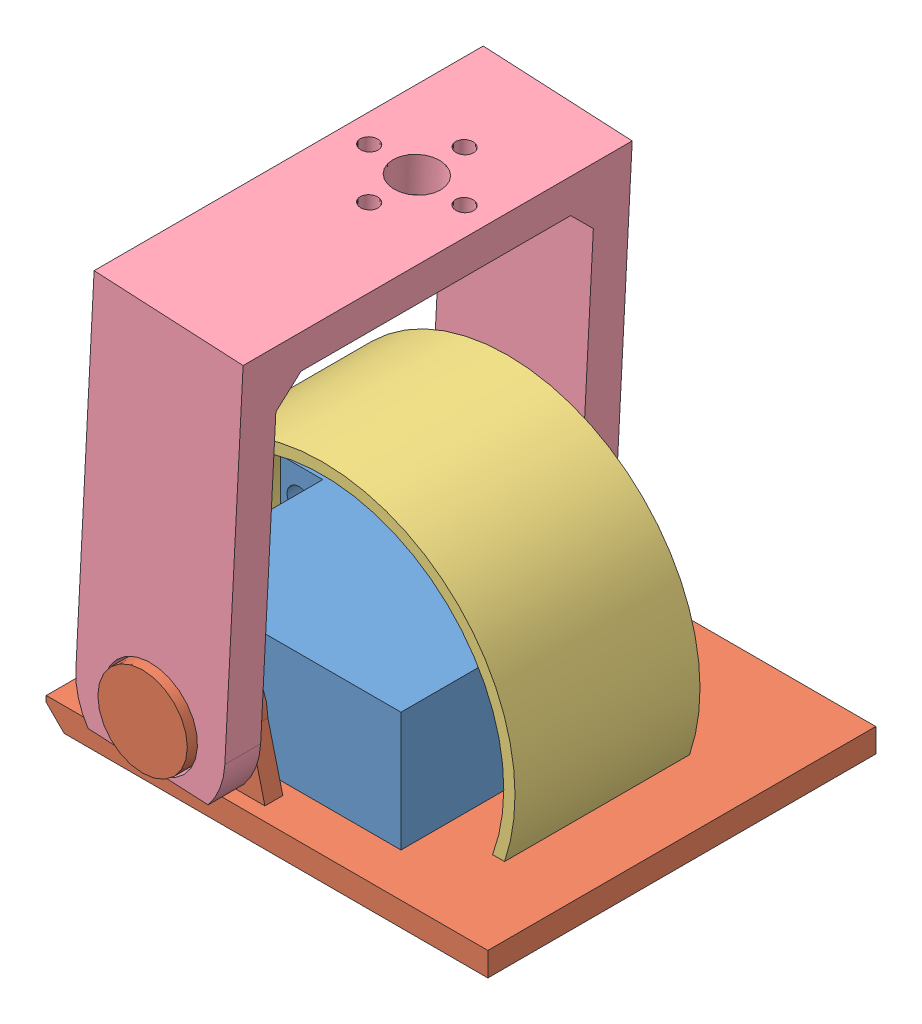
SolidWorks assembly Montaje, configuration Predeterminado. Lengths in mm.
Overall size (74.26 74.06 70.7).
4 component instances, 4 part files, 10 mates.
Components (placement in the parent):
- motor 996R-1: motor 996R [Predeterminado] at (-11.5098 -10.0295 59.1) size (54.5 21 47.5)
- Pie_DER-1: Pie_DER [Predeterminado] at (-9.5891 -14.0295 56.1) x (-1 0 0) z (0 0 -1) size (74 27.39 70.7)
- Zapato_DER-1: Zapato_DER [Predeterminado] at (-14.3651 -11.1811 40.6) size (64.51 42.76 31)
- Pierna-1: Pierna [Predeterminado] at (-8.6706 9.1482 57.7) x (-0.998677 0.051431 0) z (0 0 -1) size (25 66.91 65.2)
Mates (geometry in assembly coordinates):
- Coincidente5: coincident anti-aligned: plane of motor 996R-1 through (-11.5098 -10.0295 59.1) normal (0 -1 0); plane of Pie_DER-1 through (-9.5891 -10.0295 56.1) normal (0 1 0)
- Coincidente6: coincident anti-aligned: plane of motor 996R-1 through (8.6402 9.9705 48.6) normal (0 0 -1); plane of Pie_DER-1 through (15.7402 7.9705 48.6) normal (0 0 1)
- Coincidente7: coincident anti-aligned: plane of Pie_DER-1 through (15.7402 7.9705 43.6) normal (0 0 -1); plane of Zapato_DER-1 through (-11.5098 0.4705 43.6) normal (0 0 1)
- Paralelo1: parallel anti-aligned: plane of Pie_DER-1 through (-9.5891 -10.0295 56.1) normal (0 1 0); plane of Zapato_DER-1 through (8.9902 -10.0295 43.6) normal (0 -1 0)
- Coincidente12: coincident anti-aligned: plane of motor 996R-1 through (8.6402 9.9705 48.6) normal (0 0 -1); plane of Pie_DER-1 through (15.7402 7.9705 48.6) normal (0 0 1)
- Coincidente13: coincident aligned: circle of motor 996R-1; circle of Pie_DER-1
- Coincidente14: coincident anti-aligned: plane of motor 996R-1 through (-21.6598 -0.0295 31.1) normal (0 0 -1); plane of Pierna-1 through (-34.6833 -9.8727 31.1) normal (0 0 1)
- Concéntrica1: concentric aligned: circle of Pie_DER-1; circle of Pierna-1
- Coincidente15: coincident anti-aligned: plane of Pie_DER-1 through (-9.5891 -10.0295 56.1) normal (0 1 0); plane of Zapato_DER-1 through (-32.0098 -10.0295 43.6) normal (0 -1 0)
- Concéntrica2: concentric anti-aligned: circle of Pie_DER-1; circle of Zapato_DER-1
